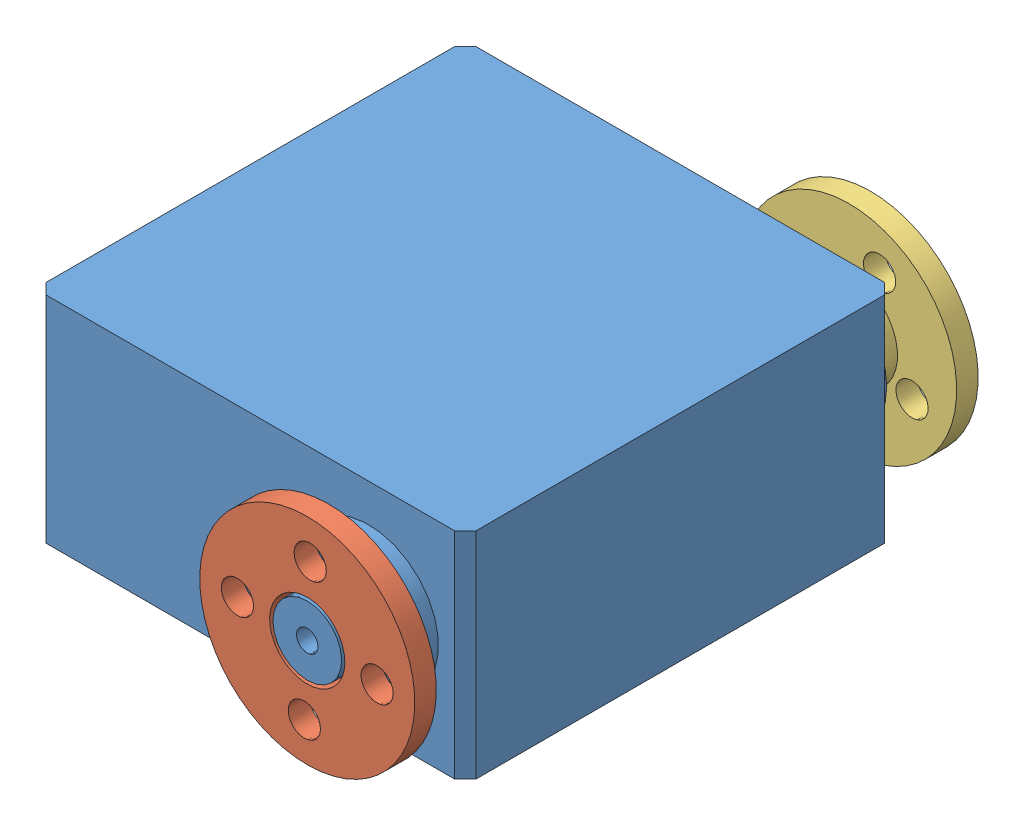
SolidWorks assembly servo_gear, configuration 默认. Lengths in mm.
Overall size (44.36 26.71 52.4).
3 component instances, 3 part files, 4 mates.
Components (placement in the parent):
- 舵机-1: 舵机 [默认] at (546.9248 215.0277 274.2891) x (-1 0 0) z (0 0 -1) size (40 20 48.7)
- 无齿盘-1: 无齿盘 [默认] at (596.5682 225.0277 306.1388) x (-0.041997 -0.999118 0) z (0.999118 -0.041997 0) size (20 3 20)
- 有齿盘-1: 有齿盘 [默认] at (596.5682 225.0277 253.7388) x (0.900229 -0.435417 0) z (-0.435417 -0.900229 0) size (20 4.2 20)
Mates (geometry in assembly coordinates):
- 距离2: distance = 1 mm anti-aligned: plane of 无齿盘-1 through (596.5682 225.0277 303.1388) normal (0 0 -1); plane of 舵机-1 through (596.5682 225.0277 302.1388) normal (0 0 1)
- 同心1: concentric anti-aligned: cylinder of 舵机-1 through (596.5682 225.0277 306.1388) axis (0 0 -1) radius 3.2; cylinder of 无齿盘-1 through (596.5682 225.0277 303.1388) axis (0 0 1) radius 3.5
- 同心2: concentric aligned: cylinder of 舵机-1 through (596.5682 225.0277 257.4388) axis (0 0 1) radius 2.5; cylinder of 有齿盘-1 through (596.5682 225.0277 255.7388) axis (0 0 1) radius 2.5
- 距离5: distance = 0.8 mm anti-aligned: plane of 舵机-1 through (596.5682 225.0277 258.7388) normal (0 0 -1); plane of 有齿盘-1 through (596.5682 225.0277 257.9388) normal (0 0 1)
